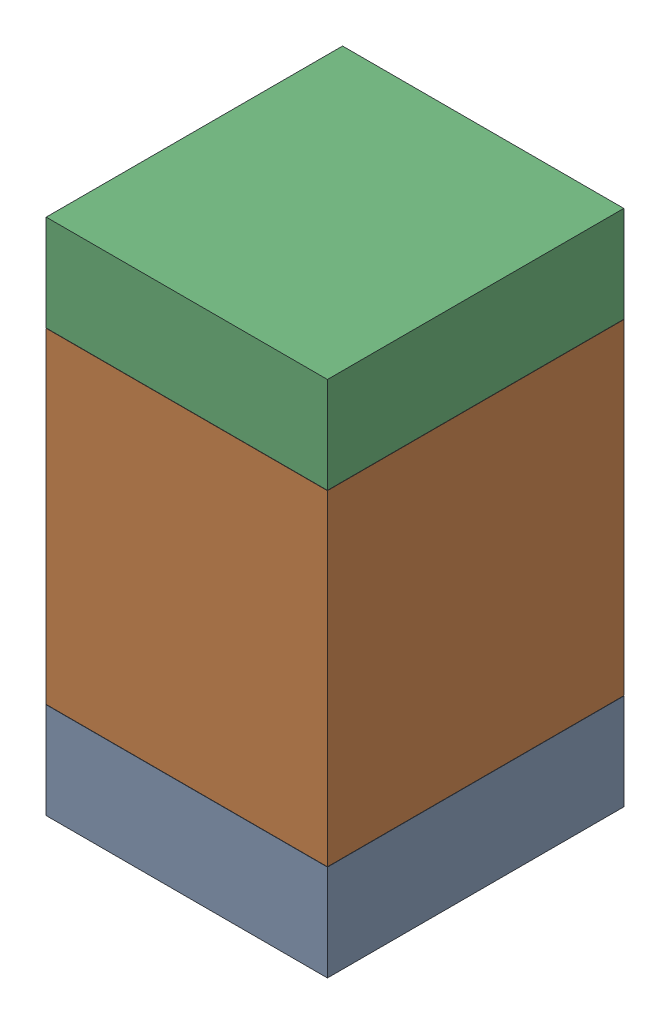
SolidWorks assembly R4, configuration Default. Lengths in mm.
Overall size (0.95 1.75 1).
6 component instances, 2 part files, 0 mates.
Components (placement in the parent):
- 6575495072-1: 6575495072 [Default] at (5.08 42.5945 0) size (0.95 0.32 1)
  - Extruded_6-1: Extruded_6 [Default] at origin size (0.95 0.32 1)
- 6575494912-1: 6575494912 [Default] at (5.08 43.307 0) size (0.95 1.1 1)
  - Extruded_7-1: Extruded_7 [Default] at origin size (0.95 1.1 1)
- 6575495072-2: 6575495072 [Default] at (5.08 44.0195 0) size (0.95 0.32 1)
  - Extruded_6-1: Extruded_6 [Default] at origin size (0.95 0.32 1)
